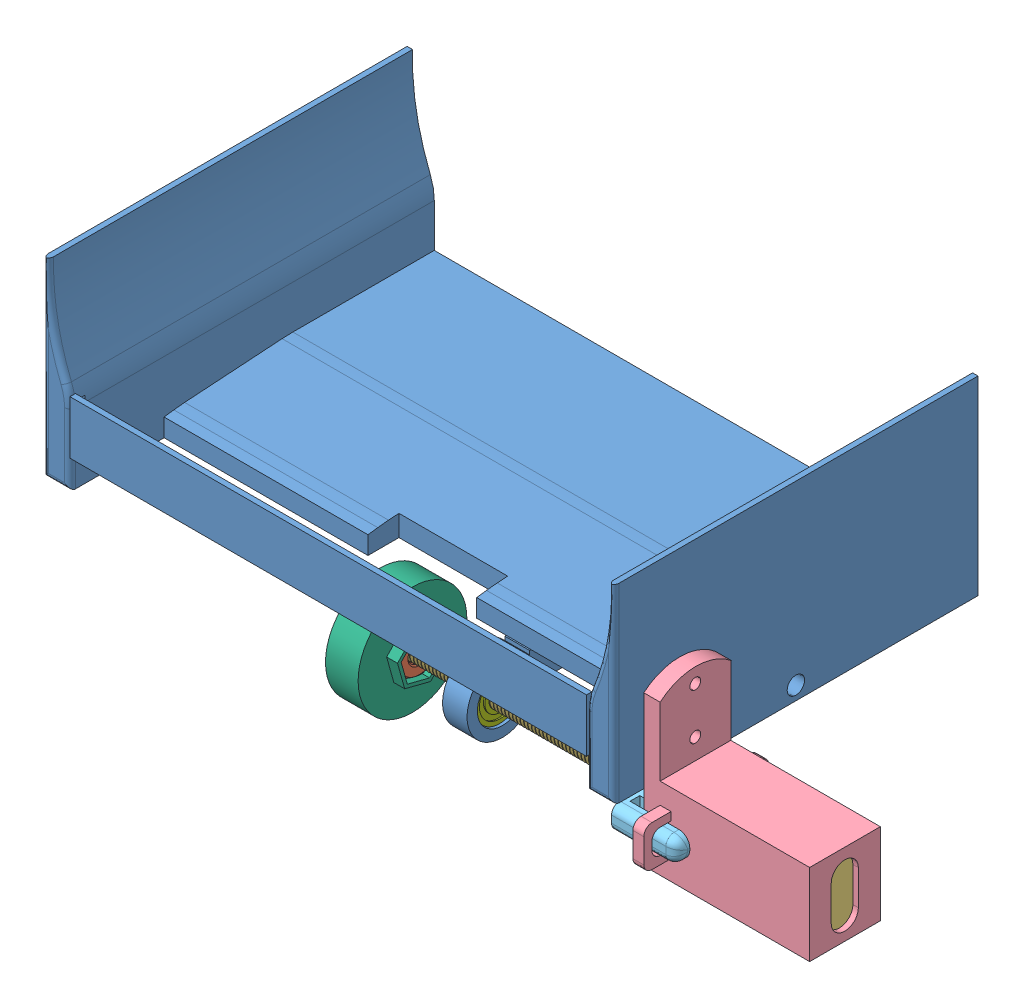
SolidWorks assembly side platform assembly (left), configuration Default. Lengths in mm.
Overall size (145.65 70.46 100.15).
8 component instances, 7 part files, 3 mates.
Components (placement in the parent):
- left platform-1: left platform [Default] at (23.4546 48.6452 53.2546) size (105 46.66 67)
- Motor& Roller Assembly-1: Motor& Roller Assembly [Default] at (41.0357 3.4912 56.9525) x (0.029593 -0.888476 -0.457967) z (-0.950879 -0.166268 0.261122) size (38.09 49.96 91.68)
  - M4 Nut-1: M4 Nut [Default] at (-57.6078 23.6231 20.5659) x (-0.029593 -0.308146 0.950879) z (-0.746697 -0.625603 -0.225974) size (3.68 8.08 7)
  - New Motor-1: New Motor [Default] at (-55.0798 47.2645 -54.1441) x (0.888476 0.427744 0.166268) z (-0.029593 -0.308146 0.950879) size (12 10.57 80.84)
  - New Motor case2-1: New Motor case2 [Default] at (-61.0264 35.7877 -27.0245) x (0.457967 -0.849754 -0.261122) z (0.029593 0.308146 -0.950879) size (23 30 30.5)
  - New Motor enclosure-1: New Motor enclosure [Default] at (-56.0797 37.2316 -23.2476) x (0.457967 -0.849754 -0.261122) z (0.029593 0.308146 -0.950879) size (18.9 5.4 12)
  - New Motor roller-1: New Motor roller [Default] at (-57.4381 24.395 18.2973) x (0.972856 0.20955 0.098185) z (-0.029593 -0.308146 0.950879) size (20 20 8)
  - Bearing-1: Bearing [Default] at (-57.0267 27.371 7.1805) x (0.911456 -0.398837 -0.100882) z (0.410332 0.863699 0.292664) size (9 4 9)
Mates (geometry in assembly coordinates):
- Concentric1: concentric aligned: cylinder of left platform-1 through (72.4546 52.6452 108.2546) axis (1 0 0) radius 1.05; cylinder of Motor& Roller Assembly-1/New Motor case2-1 through (75.9546 52.6452 108.2546) axis (1 0 0) radius 1
- Coincident1: coincident anti-aligned: plane of left platform-1 through (75.9546 63.6452 86.7546) normal (1 0 0); plane of Motor& Roller Assembly-1/New Motor case2-1 through (75.9546 53.6603 108.1288) normal (-1 0 0)
- Parallel1: parallel aligned: plane of left platform-1 through (70.9546 46.1452 120.2546) normal (0 0 1); plane of Motor& Roller Assembly-1/New Motor case2-1 through (106.4546 48.8398 114.7194) normal (0 0 1)
